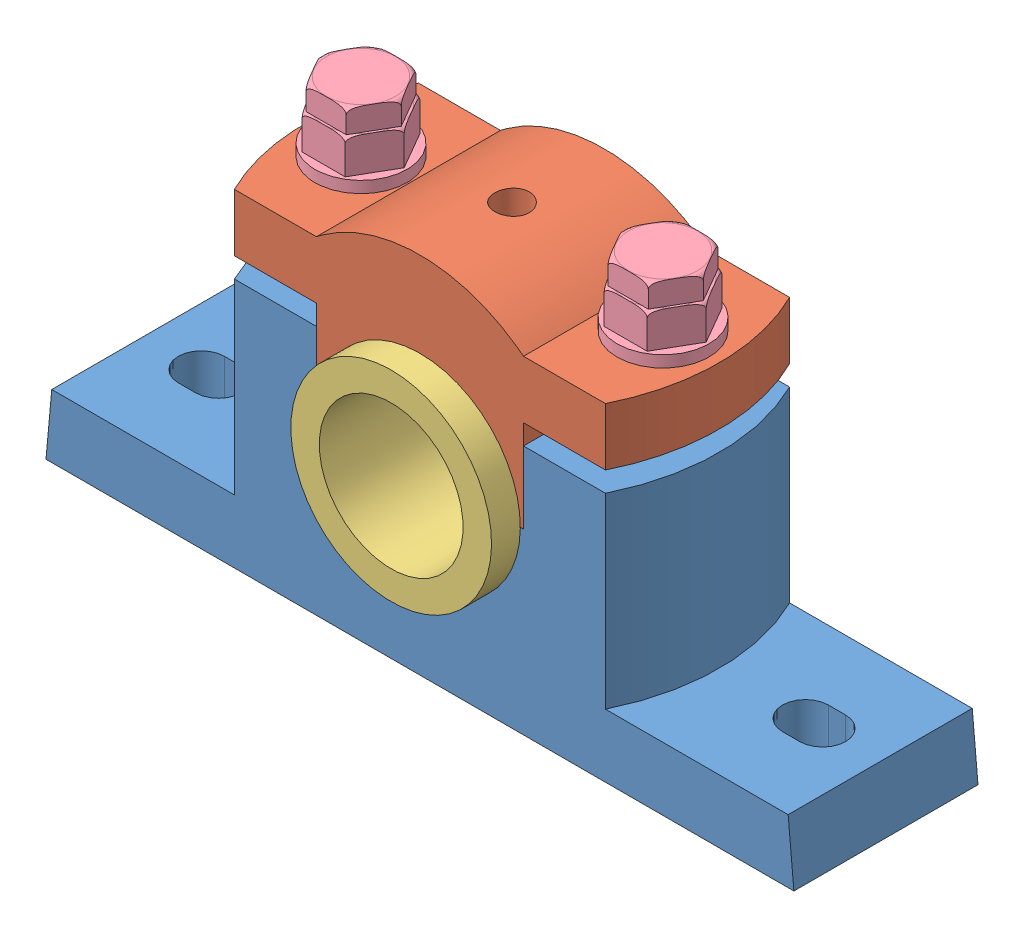
SolidWorks assembly Assem1, configuration Default. Lengths in mm.
Overall size (260 148.59 84).
5 component instances, 4 part files, 12 mates.
Components (placement in the parent):
- Bass-1: Bass [Default] at (107.8502 101.6689 194.9027) size (260 87 64)
- Cap-1: Cap [Default] at (107.8502 152.6689 194.9027) size (144 64.52 64)
- Part1-1: Part1 [Default] at (107.8502 152.6689 194.9027) x (-0.084423 0.99643 0) z (-0.99643 -0.084423 0) size (69.77 84 69.77)
- bolt with nuts-1: bolt with nuts [Default] at (55.3502 159.6689 194.9027) size (32 148.59 32)
- bolt with nuts-2: bolt with nuts [Default] at (160.3502 159.6689 194.9027) x (-1 0 0) z (0 0 -1) size (32 148.59 32)
Mates (geometry in assembly coordinates):
- Coincident1: coincident anti-aligned: plane of Bass-1 through (107.8502 152.6689 130.9027) normal (0 1 0); plane of Cap-1 through (71.8502 152.6689 226.9027) normal (0 -1 0)
- Coincident2: coincident anti-aligned: plane of Bass-1 through (107.8502 152.6689 130.9027) normal (0 1 0); plane of Cap-1 through (139.8502 152.6689 226.9027) normal (0 -1 0)
- Coincident3: coincident anti-aligned: plane of Bass-1 through (71.8502 101.6689 130.9027) normal (1 0 0); plane of Cap-1 through (71.8502 184.6689 226.9027) normal (-1 0 0)
- Coincident4: coincident anti-aligned: plane of Bass-1 through (143.8502 101.6689 130.9027) normal (-1 0 0); plane of Cap-1 through (143.8502 152.6689 226.9027) normal (1 0 0)
- Coincident5: coincident anti-aligned: plane of Bass-1 through (107.8502 152.6689 130.9027) normal (0 1 0); plane of Cap-1 through (71.8502 152.6689 226.9027) normal (0 -1 0)
- Parallel1: parallel anti-aligned: plane of Bass-1 through (107.8502 177.6689 194.9027) normal (0 1 0); plane of Cap-1 through (143.8502 184.6689 226.9027) normal (0 -1 0)
- Coincident8: coincident aligned: plane of Bass-1 through (107.8502 101.6689 194.9027) normal (0 0 1); plane of Cap-1 through (107.8502 152.6689 194.9027) normal (0 0 1)
- Concentric1: concentric anti-aligned: cylinder of Bass-1 through (107.8502 152.6689 176.9027) axis (0 0 1) radius 34; cylinder of Part1-1 through (107.8502 152.6689 152.9027) axis (0 0 -1) radius 30
- Concentric2: concentric aligned: circle of Cap-1; circle of Part1-1
- Coincident9: coincident anti-aligned: plane of Cap-1 through (107.8502 152.6689 162.9027) normal (0 0 -1); plane of Part1-1 through (105.1487 184.5546 162.9027) normal (0 0 1)
- Concentric3: concentric aligned: cylinder of Bass-1 through (55.3502 81.6689 194.9027) axis (0 1 0) radius 9.5; cylinder of bolt with nuts-1 through (55.3502 204.6689 194.9027) axis (0 1 0) radius 8
- Coincident10: coincident anti-aligned: plane of Cap-1 through (35.8502 204.6689 226.9027) normal (0 1 0); plane of bolt with nuts-1 through (55.3502 204.6689 194.9027) normal (0 -1 0)
